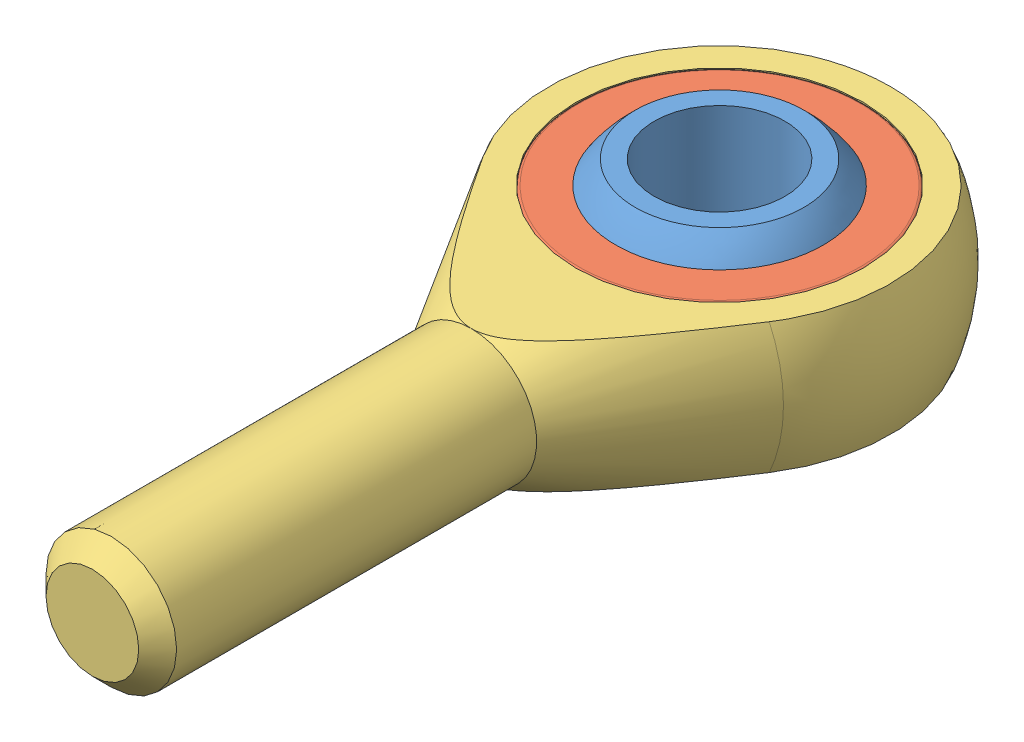
SolidWorks assembly Przegub kulowy_GN 648.2_10, configuration Domyślna. Lengths in mm.
Overall size (28 14 62).
3 component instances, 3 part files, 8 mates.
Components (placement in the parent):
- ROD-END-GN-648.2-1-10-1: ROD-END-GN-648.2-1-10 [10] x (-1 0 0) z (0 0 -1) size (19.04 14 19.04)
- ROD-END-GN-648.2-2-10-1: ROD-END-GN-648.2-2-10 [10] x (0.997964 0 0.063787) z (-0.063787 0 0.997964) size (22 10.5 22)
- ROD-END-GN-648.2-3-10-1: ROD-END-GN-648.2-3-10 [10] at (0 0.25 0) size (28 10 62)
Mates (geometry in assembly coordinates):
- Koncentryczne1: concentric: sphere of ROD-END-GN-648.2-2-10-1; sphere of ROD-END-GN-648.2-1-10-1
- Limit kąta1: limit planar angle = 0 rad aligned: cylinder of ROD-END-GN-648.2-1-10-1 through (0 -11.1 0) axis (0 -1 0) radius 5
- Limit kąta2: limit planar angle = 0 rad aligned: cylinder of ROD-END-GN-648.2-2-10-1 through (0 5.25 0) axis (0 -1 0) radius 11
- Koncentryczne5: concentric anti-aligned: cylinder of ROD-END-GN-648.2-3-10-1 through (0 -4.75 0) axis (0 1 0) radius 11; cylinder of ROD-END-GN-648.2-2-10-1 through (0 5.25 0) axis (0 -1 0) radius 11
- Wspólnie1: coincident aligned: plane of ROD-END-GN-648.2-3-10-1 through (-14 5.25 19) normal (0 1 0); plane of ROD-END-GN-648.2-2-10-1 through (0 5.25 0) normal (0 1 0)
- Wspólnie2: coincident anti-aligned: plane of ROD-END-GN-648.2-1-10-1 through (0 0 0) normal (0 0 -1)
- Wspólnie3: coincident aligned: plane of ROD-END-GN-648.2-1-10-1 through (0 0 0) normal (0 1 0)
- Wspólnie4: coincident anti-aligned: plane of ROD-END-GN-648.2-1-10-1 through (0 0 0) normal (-1 0 0)
